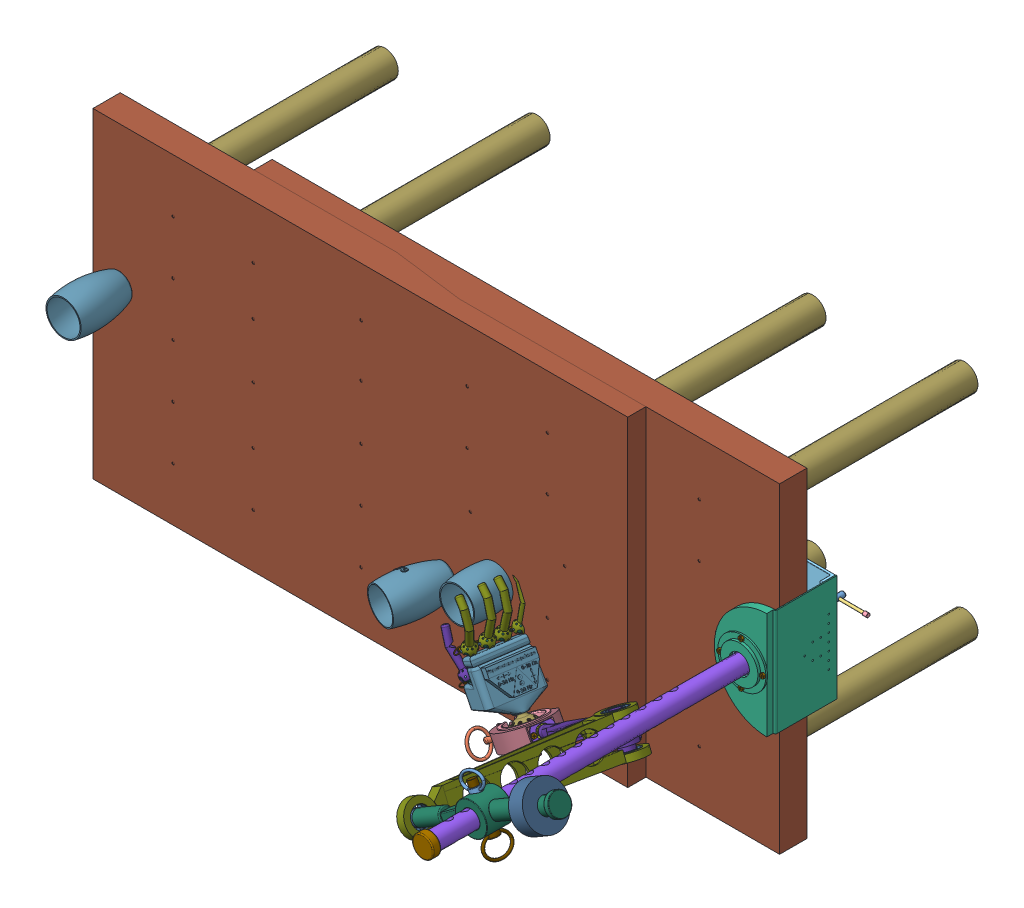
SolidWorks assembly сборка для визуализации(1,06), configuration По умолчанию. Lengths in mm.
Overall size (1361.33 660.4 1068).
77 component instances, 37 part files, 0 mates.
Components (placement in the parent):
- Зажим11-1: Зажим11 [По умолчанию] at (-561.7181 632.2224 -489.8763) x (0.99999 -0.004361 0) z (0 0 1) size (10 10 110)
- Зажим21-1: Зажим21 [По умолчанию] at (-561.7181 632.2224 -374.8763) x (0.894231 0.447606 0) z (0 0 -1) size (80 80 15)
- Ручка11-1: Ручка11 [По умолчанию] at (-506.7186 631.9825 -477.8763) x (-0.003145 -0.721164 0.692758) z (-0.99999 0.004361 0) size (7 7 100)
- Ручка21-1: Ручка21 [По умолчанию] at (-503.7186 631.9694 -477.8763) x (-0.004344 -0.996188 -0.087124) z (-0.99999 0.004361 0) size (7 7 8)
- уголок1-1: уголок1 [По умолчанию] at (-549.7181 632.2224 -412.8763) size (100 200 45)
- уголок21-1: уголок21 [По умолчанию] at (-497.7181 632.2224 -372.8763) x (0 0 1) z (-1 0 0) size (127 200 102)
- Стойка11-1: Стойка11 [По умолчанию] at (-545.243 632.2224 -299.8763) x (1 0 0) z (0 0 -1) size (90 90 9)
- Стержень11-1: Стержень11 [По умолчанию] at (-545.243 632.2224 -290.8763) x (-0.503308 0.864107 0) z (0 0 1) size (35 35 614)
- Стержень1колпак1-1: Стержень1колпак1 [По умолчанию] at (-545.243 632.2224 314.1237) x (-0.284183 -0.95877 0) z (0 0 -1) size (40 40 15)
- Шайба-вес1-1: Шайба-вес1 [По умолчанию] at (-455.3759 684.5664 198.6237) x (0.333276 -0.572187 -0.749353) z (0.864107 0.503308 0) size (80 80 30)
- Стол11-1: Стол11 [По умолчанию] at (-1249.7181 632.2224 -324.8763) size (1000 600 51)
- Стол-Ножка1-1: Стол-Ножка1 [По умолчанию] at (-1649.7181 832.2224 -719.8763) x (0.51022 -0.860044 0) z (0 0 1) size (50 50 400)
- Стол-Ножка1-2: Стол-Ножка1 [По умолчанию] at (-849.7181 432.2224 -719.8763) x (-0.098496 0.995137 0) z (0 0 1) size (50 50 400)
- Стол-Ножка1-3: Стол-Ножка1 [По умолчанию] at (-849.7181 832.2224 -719.8763) x (-0.908934 0.416939 0) z (0 0 1) size (50 50 400)
- Стол-Ножка1-4: Стол-Ножка1 [По умолчанию] at (-1649.7181 432.2224 -719.8763) x (0.814617 -0.579999 0) z (0 0 1) size (50 50 400)
- Вращение-обхват1-1: Вращение-обхват1 [По умолчанию] at (-887.057 359.5242 -231.4406) x (0.233424 0.07772 -0.969264) z (-0.514719 0.85557 -0.055354) size (97.5 109.9 30)
- Стакан1-1: Стакан1 [По умолчанию] at (-1700.9508 668.9222 -274.8763) x (1 0 0) z (0 -1 0) size (72.92 104.75 74.31)
- Шайба-крепление1НОВ1-1: Шайба-крепление1НОВ1 [По умолчанию] at (-545.243 632.2224 173.6237) x (-0.864107 -0.503308 0) z (0 0 1) size (315 60.16 50)
- Стержень2НОВ1-1: Стержень2НОВ1 [По умолчанию] at (-667.4059 553.8644 -168.6407) x (0.864107 0.503308 0) z (0.500134 -0.858656 0.112139) size (60 425.65 70)
- Стержень4(НОВ)1-1: Стержень4(НОВ)1 [По умолчанию] at (-658.7293 523.0916 -130.8551) x (0.500134 -0.858656 0.112139) z (0.252231 0.020567 -0.967448) size (70 275.07 68)
- болт1-1: болт1 [По умолчанию] at (-569.4018 673.6995 198.6237) x (-0.007622 -0.004439 0.999961) z (0.503308 -0.864107 0) size (56.65 20 118.47)
- Болт-шайба1-1: Болт-шайба1 [По умолчанию] at (-563.8654 664.1943 198.6237) x (-0.864096 -0.503302 0.005011) z (0.503308 -0.864107 0) size (51.87 20 36.08)
- болт(мал)1-1: болт(мал)1 [По умолчанию] at (-935.5434 345.7244 -264.8581) x (0.471934 -0.880583 0.043045) z (-0.233424 -0.07772 0.969264) size (49.05 10 89.62)
- Болт-шайба(мал))1-1: Болт-шайба(мал))1 [По умолчанию] at (-930.875 347.2788 -284.2434) x (-0.47412 0.879377 -0.043668) z (-0.233424 -0.07772 0.969264) size (59.77 10 62.36)
- прокладка1-1: прокладка1 [По умолчанию] at (-887.057 359.5242 -231.4406) x (0.824971 0.51182 0.239715) z (-0.514719 0.85557 -0.055354) size (72.67 75 34.29)
- Bearing GB-T 292-2007 Type IN B7007 C1-1: Bearing GB-T 292-2007 Type IN B7007 C1 [По умолчанию] at (-545.243 632.2224 -299.8763) x (0 0 1) z (-0.706224 -0.707988 0) size (14 62 62)
- крышка21-1: крышка21 [По умолчанию] at (-545.243 632.2224 -282.8763) x (0 -1 0) z (0 0 1) size (90 90 8)
- Bearing GB-T 292-2007 Type IN B7000 C1-1: Bearing GB-T 292-2007 Type IN B7000 C1 [По умолчанию] at (-861.1602 393.2144 -222.5025) x (0.824971 0.51182 0.239715) z (-0.265382 0.725278 -0.635252) size (8 26 26)
- крышка31-1: крышка31 [По умолчанию] at (-852.9105 398.3326 -220.1053) x (-0.514719 0.85557 -0.055354) z (-0.824971 -0.51182 -0.239715) size (25.5 40 2)
- Bolt GB-T 29-2-1988 M5x101-1: Bolt GB-T 29-2-1988 M5x101 [По умолчанию] at (-856.762 397.0503 -204.1125) x (-0.824971 -0.51182 -0.239715) z (0.391313 -0.211232 -0.895687) size (13.5 9.24 8)
- Bolt GB-T 29-2-1988 M5x101-2: Bolt GB-T 29-2-1988 M5x101 [По умолчанию] at (-849.059 399.615 -236.0982) x (-0.824971 -0.51182 -0.239715) z (-0.546943 0.61613 0.566778) size (13.5 9.24 8)
- Bolt GB-T 29-2-1988 M5x101-3: Bolt GB-T 29-2-1988 M5x101 [По умолчанию] at (-545.243 592.2224 -282.8763) x (0 0 -1) z (0.940322 -0.340286 0) size (13.5 9.24 8)
- Bolt GB-T 29-2-1988 M5x101-4: Bolt GB-T 29-2-1988 M5x101 [По умолчанию] at (-545.243 596.2224 -304.8763) x (0 0 1) z (0.166538 -0.986035 0) size (13.5 9.24 8)
- Bolt GB-T 29-2-1988 M5x101-5: Bolt GB-T 29-2-1988 M5x101 [По умолчанию] at (-514.0661 614.2224 -304.8763) x (0 0 1) z (0.888034 -0.459778 0) size (13.5 9.24 8)
- Bolt GB-T 29-2-1988 M5x101-6: Bolt GB-T 29-2-1988 M5x101 [По умолчанию] at (-576.4199 614.2224 -304.8763) x (0 0 1) z (0.845985 -0.533207 0) size (13.5 9.24 8)
- Bolt GB-T 29-2-1988 M5x101-7: Bolt GB-T 29-2-1988 M5x101 [По умолчанию] at (-514.0661 650.2224 -304.8763) x (0 0 1) z (-0.991097 0.133139 0) size (13.5 9.24 8)
- Bolt GB-T 29-2-1988 M5x101-8: Bolt GB-T 29-2-1988 M5x101 [По умолчанию] at (-545.243 672.2224 -282.8763) x (0 0 -1) z (0.336175 -0.941799 0) size (13.5 9.24 8)
- Bolt GB-T 29-2-1988 M5x101-9: Bolt GB-T 29-2-1988 M5x101 [По умолчанию] at (-505.243 632.2224 -282.8763) x (0 0 -1) z (0.420157 -0.907451 0) size (13.5 9.24 8)
- Bolt GB-T 29-2-1988 M5x101-10: Bolt GB-T 29-2-1988 M5x101 [По умолчанию] at (-576.4199 650.2224 -304.8763) x (0 0 1) z (0.716794 0.697285 0) size (13.5 9.24 8)
- Bolt GB-T 29-2-1988 M5x101-11: Bolt GB-T 29-2-1988 M5x101 [По умолчанию] at (-545.243 668.2224 -304.8763) x (0 0 1) z (0.937659 -0.347558 0) size (13.5 9.24 8)
- Bolt GB-T 29-2-1988 M5x101-12: Bolt GB-T 29-2-1988 M5x101 [По умолчанию] at (-585.243 632.2224 -282.8763) x (0 0 -1) z (0.836585 -0.547837 0) size (13.5 9.24 8)
- Bearing GB-T 292-2007 Type IN B7004 C1-1: Bearing GB-T 292-2007 Type IN B7004 C1 [По умолчанию] at (-661.4043 543.5605 -167.295) x (-0.500134 0.858656 -0.112139) z (0.571973 0.230336 -0.787269) size (12 42 42)
- Bearing GB-T 292-2007 Type IN B7004 C1-2: Bearing GB-T 292-2007 Type IN B7004 C1 [По умолчанию] at (-632.3965 493.7584 -160.791) x (-0.500134 0.858656 -0.112139) z (-0.191276 0.016758 0.981393) size (12 42 42)
- Bearing GB-T 292-2007 Type IN B7004 C1-3: Bearing GB-T 292-2007 Type IN B7004 C1 [По умолчанию] at (-675.7231 556.2228 198.6237) x (0.864107 0.503308 0) z (-0.161135 0.276645 -0.947366) size (12 42 42)
- Стол11-2: Стол11 [По умолчанию] at (-999.7181 632.2224 -358.8763) size (1000 600 51)
- Стол-Ножка1-5: Стол-Ножка1 [По умолчанию] at (-1399.7181 832.2224 -753.8763) x (0.738675 -0.674061 0) z (0 0 1) size (50 50 400)
- Стол-Ножка1-6: Стол-Ножка1 [По умолчанию] at (-1399.7181 432.2224 -753.8763) x (0.273621 -0.961838 0) z (0 0 1) size (50 50 400)
- Стол-Ножка1-7: Стол-Ножка1 [По умолчанию] at (-599.7181 432.2224 -753.8763) x (0.397888 -0.917434 0) z (0 0 1) size (50 50 400)
- Стол-Ножка1-8: Стол-Ножка1 [По умолчанию] at (-599.7181 832.2224 -753.8763) x (0.514649 -0.857401 0) z (0 0 1) size (50 50 400)
- Стакан1-2: Стакан1 [По умолчанию] at (-998.1233 539.8121 -307.8763) x (0.86163 -0.507536 0) z (-0.507536 -0.86163 0) size (72.92 104.75 74.31)
- рука-1: рука [По умолчанию] at (-799.642 469.9203 -221.7395) x (-0.824971 -0.51182 -0.239715) z (-0.514719 0.85557 -0.055354) size (271.21 189.97 308.25)
  - Wrist (Ball)-1: Wrist (Ball) [По умолчанию] at (130.9432 19.5819 -34.9204) x (1 0 0) z (0 1 0) size (42 55.8 41.57)
  - Wrist (Socket)-1: Wrist (Socket) [По умолчанию] at (130.9432 19.5819 -34.9204) x (1 0 0) z (0 -1 0) size (89.1 37 45.25)
  - Wrist (Pulley)-1: Wrist (Pulley) [По умолчанию] at (186.0432 19.5819 -33.9204) x (-0.070211 0 -0.997532) z (0 1 0) size (20 20 14)
  - Finger (Hand)-2-1: Finger (Hand)-2 [По умолчанию] at (156.7967 12.6253 74.3496) x (0.004145 0.999991 0) z (0 0 1) size (100.4 77.16 97.92)
  - Finger (Ball)-1: Finger (Ball) [По умолчанию] at (131.109 59.5815 99.3496) x (0.811963 0.583709 0) z (-0.583709 0.811963 0) size (20 22.54 19.77)
  - Finger (Socket)-1: Finger (Socket) [По умолчанию] at (131.0283 59.0881 99.3496) x (-0.580287 -0.621598 -0.526197) z (-0.352032 0.774074 -0.526197) size (38.39 91.08 37.87)
  - Finger (Ball)-2: Finger (Ball) [По умолчанию] at (130.995 32.0818 99.3496) x (-0.772654 0.634827 0) z (-0.634827 -0.772654 0) size (20 22.54 19.77)
  - Finger (Socket)-2: Finger (Socket) [По умолчанию] at (131.0437 31.5842 99.3496) x (-0.4251 -0.752117 -0.503598) z (-0.562927 0.655364 -0.503598) size (38.39 91.08 37.87)
  - Finger (Ball)-3: Finger (Ball) [По умолчанию] at (130.8913 7.082 99.3496) x (-0.135652 0.990757 0) z (-0.990757 -0.135652 0) size (20 22.54 19.77)
  - Finger (Socket)-3: Finger (Socket) [По умолчанию] at (130.8235 7.5774 99.3496) x (-0.398953 -0.768327 -0.500509) z (-0.590794 0.632814 -0.500509) size (38.39 91.08 37.87)
  - Finger (Ball)-4: Finger (Ball) [По умолчанию] at (130.7773 -20.4178 99.3496) x (-0.176458 0.984308 0) z (-0.984308 -0.176458 0) size (20 22.54 19.77)
  - Finger (Socket)-4: Finger (Socket) [По умолчанию] at (130.6891 -19.9256 99.3496) x (-0.399706 -0.790035 -0.464844) z (-0.649255 0.601987 -0.464844) size (38.39 91.08 37.87)
  - Finger (Ball)-5: Finger (Ball) [По умолчанию] at (168.6086 59.4261 60.889) x (-0.15201 0.988379 0) z (-0.988379 -0.15201 0) size (20 22.54 19.77)
  - Thumb (Socket)-1: Thumb (Socket) [По умолчанию] at (168.2055 59.7218 60.889) x (-0.161961 0.97481 -0.153344) z (0.978427 0.13844 -0.153344) size (24.44 80.4 23.92)
  - Wrist (Lock Pin)-1: Wrist (Lock Pin) [По умолчанию] at (130.8237 59.9784 99.9185) x (0.544202 -0.757007 0.361641) z (0.811963 0.583709 0) size (19.35 7.53 29.68)
  - Wrist (Lock Pin)-2: Wrist (Lock Pin) [По умолчанию] at (131.0293 32.0535 100.0983) x (0.711911 -0.584919 -0.388656) z (0.634827 0.772654 0) size (19.35 7.53 29.68)
  - Wrist (Lock Pin)-3: Wrist (Lock Pin) [По умолчанию] at (130.3129 7.5211 99.5369) x (0.444577 -0.337498 0.829727) z (0.60465 0.796491 0) size (19.35 7.53 29.68)
  - Wrist (Lock Pin)-4: Wrist (Lock Pin) [По умолчанию] at (130.6144 -20.3044 100.0729) x (0.818663 -0.56976 -0.071862) z (0.571237 0.820785 0) size (19.35 7.53 29.68)
  - Wrist (Lock Pin)-5: Wrist (Lock Pin) [По умолчанию] at (168.115 59.2086 60.368) x (-0.044313 0.993251 0.107186) z (0.69889 0.107487 -0.707107) size (19.35 7.53 29.68)
  - Finger (Pivot Pin, Short)-1: Finger (Pivot Pin, Short) [По умолчанию] at (131.0283 59.0881 99.3496) x (-0.982653 0.160707 0.092552) z (0.1614 0.986889 0) size (4 4 26)
  - Finger (Pivot Pin, Short)-2: Finger (Pivot Pin, Short) [По умолчанию] at (131.0437 31.5842 99.3496) x (-0.501883 -0.049147 0.863538) z (-0.097459 0.99524 0) size (4 4 26)
  - Finger (Pivot Pin, Short)-3: Finger (Pivot Pin, Short) [По умолчанию] at (130.8235 7.5774 99.3496) x (0.969812 0.132784 0.204533) z (0.135652 -0.990757 0) size (4 4 26)
  - Finger (Pivot Pin, Short)-4: Finger (Pivot Pin, Short) [По умолчанию] at (130.6891 -19.9256 99.3496) x (0.982199 0.176079 -0.06543) z (0.176458 -0.984308 0) size (4 4 26)
  - Finger (Pivot Pin, Short)-5: Finger (Pivot Pin, Short) [По умолчанию] at (170.2214 58.2433 60.889) x (-0.342638 -0.467186 -0.815069) z (-0.806376 0.591403 0) size (4 4 26)
  - Wrist (Lock Pin)-6: Wrist (Lock Pin) [По умолчанию] at (121.5719 30.0096 -34.8536) x (-0.17537 -0.17537 -0.968757) z (-0.707107 0.707107 0) size (19.35 7.53 29.68)
  - Стакан1-1: Стакан1 [По умолчанию] at (191.5137 30.0598 187.4764) size (72.92 104.75 74.31)
